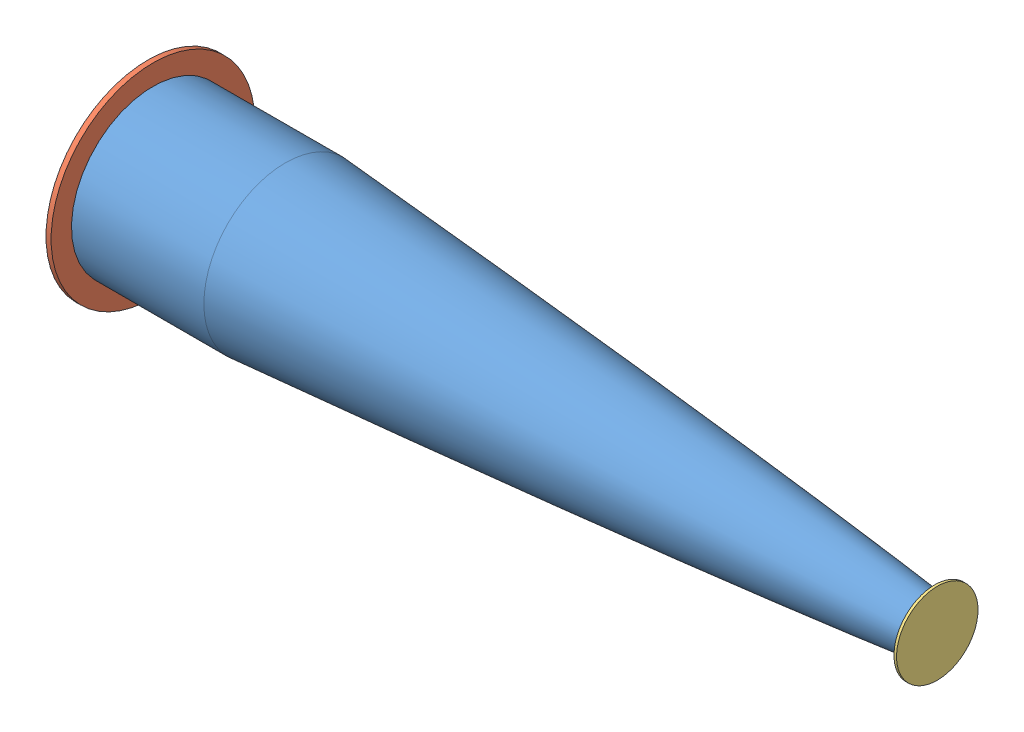
SolidWorks assembly Pressure Port Test Assembly, configuration Default. Lengths in mm.
Overall size (984.25 254 254).
3 component instances, 3 part files, 5 mates.
Components (placement in the parent):
- High Alt Nose Cone-1: High Alt Nose Cone [Default] x (-1 0 0) z (0 0 1) size (974.72 203.2 203.2)
- Lower Nosecone Testing Bulkhead-1: Lower Nosecone Testing Bulkhead [Default] at (-171.45 101.6 0) x (0 -1 0) z (0 0 1) size (254 6.35 254)
- Upper Nosecone Testing Bulkhead-1: Upper Nosecone Testing Bulkhead [Default] at (812.8 101.6 0) x (0 1 0) z (0 0 1) size (101.6 3.17 101.6)
Mates (geometry in assembly coordinates):
- Coincident1: coincident anti-aligned: plane of High Alt Nose Cone-1 through (-165.1 101.6 0) normal (-1 0 0); plane of Lower Nosecone Testing Bulkhead-1 through (-165.1 101.6 0) normal (1 0 0)
- Concentric1: concentric aligned: cylinder of High Alt Nose Cone-1 through (0 101.6 0) axis (-1 0 0) radius 101.6; cylinder of Lower Nosecone Testing Bulkhead-1 through (-165.1 101.6 0) axis (-1 0 0) radius 127
- Parallel1: parallel aligned: plane of High Alt Nose Cone-1 through (0 0 0) normal (0 0 1); plane of Lower Nosecone Testing Bulkhead-1 through (-171.45 101.6 0) normal (0 0 1)
- Coincident5: coincident anti-aligned: plane of High Alt Nose Cone-1 through (809.625 70.8591 0) normal (1 0 0); plane of Upper Nosecone Testing Bulkhead-1 through (809.625 101.6 0) normal (-1 0 0)
- Concentric2: concentric anti-aligned: circle of High Alt Nose Cone-1; cylinder of Upper Nosecone Testing Bulkhead-1 through (809.625 101.6 0) axis (1 0 0) radius 50.8
